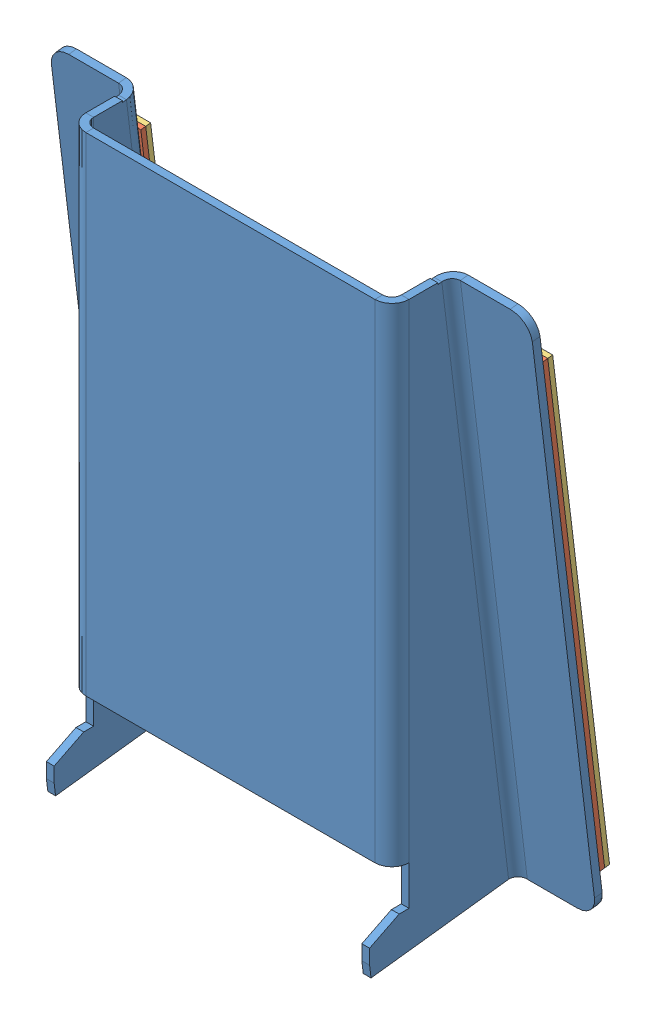
SolidWorks assembly FE-00305, configuration Default. Lengths in mm.
Overall size (154.9 183.47 51.91).
5 component instances, 3 part files, 12 mates.
Components (placement in the parent):
- FE-00304-1: FE-00304 [side lock] at (55.9838 67.4276 185.6706) size (154.9 183.47 50.28)
- Hook_1_6-1: Hook_1_6 [Default] at (109.2838 142.92 160.8781) x (0 -0.992735 -0.120323) z (-1 0 0) size (152.4 1.59 25.4)
- Hook_1_6-2: Hook_1_6 [Default] at (5.1838 142.729 162.4541) x (0 -0.992735 -0.120323) z (1 0 0) size (152.4 1.59 25.4)
- Loop_1_6-1: Loop_1_6 [Default] at (-20.2162 143.111 159.3022) x (0 -0.992735 -0.120323) z (-1 0 0) size (152.4 1.59 25.4)
- Loop_1_6-2: Loop_1_6 [Default] at (109.2838 143.111 159.3022) x (0 -0.992735 -0.120323) z (-1 0 0) size (152.4 1.59 25.4)
Mates (geometry in assembly coordinates):
- Coincident1: coincident anti-aligned: plane of FE-00304-1 through (55.9838 71.291 153.7956) normal (0 0.120323 -0.992735); plane of Hook_1_6-1 through (109.2838 142.729 162.4541) normal (0 -0.120323 0.992735)
- Coincident2: coincident anti-aligned: line of FE-00304-1 through (134.6838 150.3246 163.3747) axis (0 -0.992735 -0.120323); line of Hook_1_6-1 through (134.6838 -8.5638 144.1169) axis (0 0.992735 0.120323)
- Distance1: distance = 12.7 mm: plane of FE-00304-1 through (109.2838 -21.1715 142.5888) normal (0 -0.992735 -0.120323); line of Hook_1_6-1 through (109.2838 -8.3728 142.5409) axis (1 0 0)
- Coincident6: coincident anti-aligned: plane of FE-00304-1 through (55.9838 71.291 153.7956) normal (0 0.120323 -0.992735); plane of Hook_1_6-2 through (5.1838 142.729 162.4541) normal (0 -0.120323 0.992735)
- Distance2: distance = 12.7 mm aligned: plane of FE-00304-1 through (-20.2162 -21.1715 142.5888) normal (0 -0.992735 -0.120323); plane of Hook_1_6-2 through (5.1838 -8.3728 142.5409) normal (0 -0.992735 -0.120323)
- Coincident8: coincident aligned: plane of FE-00304-1 through (-20.2162 156.6285 164.1388) normal (-1 0 0); plane of Hook_1_6-2 through (-20.2162 142.92 160.8781) normal (-1 0 0)
- Coincident9: coincident anti-aligned: plane of Hook_1_6-2 through (5.1838 142.92 160.8781) normal (0 0.120323 -0.992735); plane of Loop_1_6-1 through (-20.2162 142.92 160.8781) normal (0 -0.120323 0.992735)
- Coincident10: coincident aligned: plane of Hook_1_6-2 through (5.1838 142.92 160.8781) normal (1 0 0); plane of Loop_1_6-1 through (5.1838 142.92 160.8781) normal (1 0 0)
- Coincident11: coincident aligned: plane of Hook_1_6-2 through (5.1838 -8.3728 142.5409) normal (0 -0.992735 -0.120323); plane of Loop_1_6-1 through (-20.2162 -8.3728 142.5409) normal (0 -0.992735 -0.120323)
- Coincident12: coincident anti-aligned: plane of Hook_1_6-1 through (109.2838 142.92 160.8781) normal (0 0.120323 -0.992735); plane of Loop_1_6-2 through (109.2838 142.92 160.8781) normal (0 -0.120323 0.992735)
- Coincident13: coincident aligned: line of Hook_1_6-1 through (134.6838 -8.5638 144.1169) axis (0 0.992735 0.120323); plane of Loop_1_6-2 through (134.6838 142.92 160.8781) normal (1 0 0)
- Coincident14: coincident aligned: plane of Hook_1_6-2 through (5.1838 -8.3728 142.5409) normal (0 -0.992735 -0.120323); plane of Loop_1_6-2 through (109.2838 -8.3728 142.5409) normal (0 -0.992735 -0.120323)
